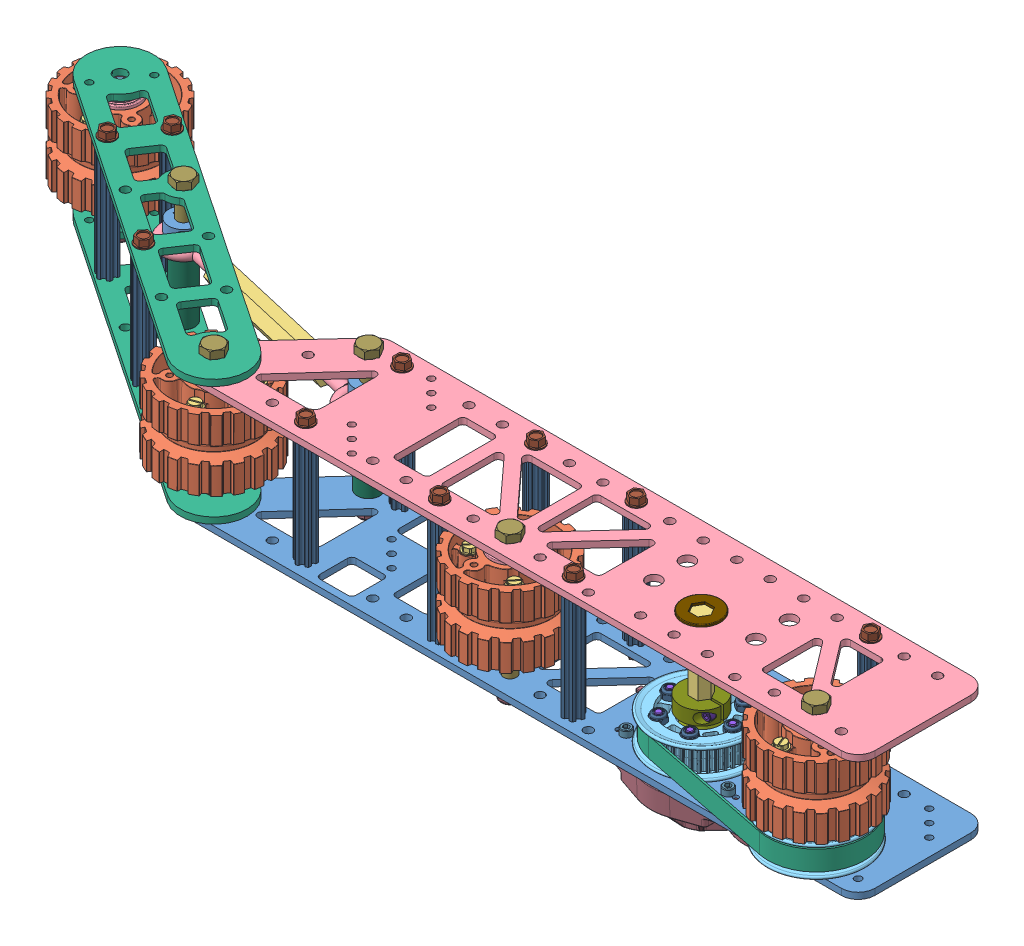
SolidWorks assembly TankDriveLeftSide, configuration Left Side. Lengths in mm.
Overall size (767.37 153.17 246.6).
161 component instances, 41 part files, 0 mates.
Components (placement in the parent):
- am-3319 Inside Plate-1: am-3319 Inside Plate [Default] at (-236.8957 -8.1516 48.6059) size (527.05 4.76 117.47)
- 20T pulley back to back-1: 20T pulley back to back [Default] at (-161.7045 40.7669 -11.83) x (0.939367 0 -0.342914) z (0.342914 0 0.939367) size (79.28 58.42 79.28)
  - am-3298 20 tooth Molded Tank Pulley Half r3-1: am-3298 20 tooth Molded Tank Pulley Half r3 [Default] at (-66.929 10.7589 19.6249) size (79.28 27.95 79.28)
  - am-3298 20 tooth Molded Tank Pulley Half r3-2: am-3298 20 tooth Molded Tank Pulley Half r3 [Default] at (-66.929 10.7589 19.6249) x (1 0 0) z (0 0 -1) size (79.28 27.95 79.28)
  - 10-24 Hex Washer Rolling x 1.25_93882A213-1: 10-24 Hex Washer Rolling x 1.25_93882A213 [Default] at (-46.3067 30.1899 7.7187) x (1 0 0) z (0 1 0) size (10.52 10.52 35.59)
  - 10-24 Hex Washer Rolling x 1.25_93882A213-2: 10-24 Hex Washer Rolling x 1.25_93882A213 [Default] at (-87.5512 30.1899 7.7187) x (1 0 0) z (0 1 0) size (10.52 10.52 35.59)
  - 10-24 Hex Washer Rolling x 1.25_93882A213-3: 10-24 Hex Washer Rolling x 1.25_93882A213 [Default] at (-66.929 30.1899 43.4374) x (1 0 0) z (0 1 0) size (10.52 10.52 35.59)
  - 10-24 Hex Washer Rolling x 1.25_93882A213-4: 10-24 Hex Washer Rolling x 1.25_93882A213 [Default] at (-66.929 -8.6721 -4.1876) x (-0.837169 0 -0.546944) z (0 -1 0) size (10.52 10.52 35.59)
  - 10-24 Hex Washer Rolling x 1.25_93882A213-5: 10-24 Hex Washer Rolling x 1.25_93882A213 [Default] at (-87.5512 -8.6721 31.5312) x (-0.837169 0 -0.546944) z (0 -1 0) size (10.52 10.52 35.59)
  - 10-24 Hex Washer Rolling x 1.25_93882A213-6: 10-24 Hex Washer Rolling x 1.25_93882A213 [Default] at (-46.3067 -8.6721 31.5312) x (-0.837169 0 -0.546944) z (0 -1 0) size (10.52 10.52 35.59)
  - 1614Z Bearing-1: 1614Z Bearing [Default] at (-66.929 -13.6886 19.6249) x (1 0 0) z (0 1 0) size (28.58 28.58 9.53)
  - 1614Z Bearing-2: 1614Z Bearing [Default] at (-66.929 35.2064 19.6249) x (1 0 0) z (0 -1 0) size (28.58 28.58 9.53)
- am-1393 375 washer-1: am-1393 375 washer [Default] at (-217.8457 80.7357 29.5559) size (20.62 1.6 20.62)
- am-3320 Upper Bar-1: am-3320 Upper Bar [Default] at (-436.3178 87.0984 -117.8054) x (0.829038 0 0.559193) z (-0.559193 0 0.829038) size (314.32 4.76 50.8)
- am-3320 Upper Bar-2: am-3320 Upper Bar [Default] at (-436.3178 -3.3891 -117.8054) x (0.829038 0 0.559193) z (-0.559193 0 0.829038) size (314.32 4.76 50.8)
- 20T pulley back to back-2: 20T pulley back to back [Default] at (-369.3889 40.7669 -137.4304) size (79.28 58.42 79.28)
  - am-3298 20 tooth Molded Tank Pulley Half r3-1: am-3298 20 tooth Molded Tank Pulley Half r3 [Default] at (-66.929 10.7589 19.6249) size (79.28 27.95 79.28)
  - am-3298 20 tooth Molded Tank Pulley Half r3-2: am-3298 20 tooth Molded Tank Pulley Half r3 [Default] at (-66.929 10.7589 19.6249) x (1 0 0) z (0 0 -1) size (79.28 27.95 79.28)
  - 10-24 Hex Washer Rolling x 1.25_93882A213-1: 10-24 Hex Washer Rolling x 1.25_93882A213 [Default] at (-46.3067 30.1899 7.7187) x (1 0 0) z (0 1 0) size (10.52 10.52 35.59)
  - 10-24 Hex Washer Rolling x 1.25_93882A213-2: 10-24 Hex Washer Rolling x 1.25_93882A213 [Default] at (-87.5512 30.1899 7.7187) x (1 0 0) z (0 1 0) size (10.52 10.52 35.59)
  - 10-24 Hex Washer Rolling x 1.25_93882A213-3: 10-24 Hex Washer Rolling x 1.25_93882A213 [Default] at (-66.929 30.1899 43.4374) x (1 0 0) z (0 1 0) size (10.52 10.52 35.59)
  - 10-24 Hex Washer Rolling x 1.25_93882A213-4: 10-24 Hex Washer Rolling x 1.25_93882A213 [Default] at (-66.929 -8.6721 -4.1876) x (-0.837169 0 -0.546944) z (0 -1 0) size (10.52 10.52 35.59)
  - 10-24 Hex Washer Rolling x 1.25_93882A213-5: 10-24 Hex Washer Rolling x 1.25_93882A213 [Default] at (-87.5512 -8.6721 31.5312) x (-0.837169 0 -0.546944) z (0 -1 0) size (10.52 10.52 35.59)
  - 10-24 Hex Washer Rolling x 1.25_93882A213-6: 10-24 Hex Washer Rolling x 1.25_93882A213 [Default] at (-46.3067 -8.6721 31.5312) x (-0.837169 0 -0.546944) z (0 -1 0) size (10.52 10.52 35.59)
  - 1614Z Bearing-1: 1614Z Bearing [Default] at (-66.929 -13.6886 19.6249) x (1 0 0) z (0 1 0) size (28.58 28.58 9.53)
  - 1614Z Bearing-2: 1614Z Bearing [Default] at (-66.929 35.2064 19.6249) x (1 0 0) z (0 -1 0) size (28.58 28.58 9.53)
- Track Belt-1: Track Belt [Default] at (269.5295 26.1257 93.0559) (suppressed, hidden)
- am-2598_107 2016 KOP Toughbox Mini-1: am-2598_107 2016 KOP Toughbox Mini [Default] at (224.1992 42.3901 20.5759) x (0.999999 0 -0.001296) z (0 1 0) size (140.05 121.81 142.29)
  - Toughbox d07-1: Toughbox d07 [Default] at (-88.5589 93.4503 -52.3959) x (-0.336928 0.94153 0) z (0.94153 0.336928 0) size (11 38.23 9.52)
  - Toughbox d05-1: Toughbox d05 [Default] at (-91.0349 50.9043 -67.5597) x (-0.336928 0.94153 0) z (0 0 -1) size (65.97 66.04 10.34)
  - FR6ZZ Bearing-1: FR6ZZ Bearing [Default] at (-96.247 60.278 -52.5991) x (-0.893862 0.448342 0) z (0 0 1) size (24.69 24.69 7.16)
  - 10-32 Nylock Nut-1: 10-32 Nylock Nut [Default] at (-129.8464 -8.0737 -56.3837) x (0.501678 0.865055 0) z (0 0 -1) size (9.53 11 5.96)
  - 10-32 Nylock Nut-2: 10-32 Nylock Nut [Default] at (-59.2462 80.7349 -56.3837) x (0.999999 -0.001296 0) z (0 0 -1) size (9.53 11 5.96)
  - 10-32 Nylock Nut-3: 10-32 Nylock Nut [Default] at (-122.7461 80.8172 -56.3837) x (0.500567 0.865698 0) z (0 0 -1) size (9.53 11 5.96)
  - 10-32 Nylock Nut-4: 10-32 Nylock Nut [Default] at (-52.3764 -8.1741 -56.3837) x (-0.501678 -0.865055 0) z (0 0 -1) size (9.53 11 5.96)
  - 5-16 washer-1: 5-16 washer [Default] at (-52.3162 38.3079 -77.7705) x (0.38418 -0.923258 0) z (0 0 -1) size (17.53 17.53 1.47)
  - 5-16 washer-2: 5-16 washer [Default] at (-52.3162 38.3079 -76.2973) x (0.897267 -0.441488 0) z (0 0 -1) size (17.53 17.53 1.47)
  - 5-16 washer-3: 5-16 washer [Default] at (-129.7861 38.4083 -77.7705) x (-0.990116 0.140253 0) z (0 0 1) size (17.53 17.53 1.47)
  - 5-16 washer-4: 5-16 washer [Default] at (-129.7861 38.4083 -79.2437) x (-0.681761 0.731575 0) z (0 0 1) size (17.53 17.53 1.47)
  - Toughbox d09-1: Toughbox d09 [Default] at (-52.3162 38.3079 -63.5973) x (0.910249 -0.414061 0) z (0 0 -1) size (20.03 20.32 12.7)
  - Toughbox d09-2: Toughbox d09 [Default] at (-129.7861 38.4083 -63.5973) x (0.075368 -0.997156 0) z (0 0 -1) size (20.03 20.32 12.7)
  - TM Housing-1: TM Housing [Default] at (-91.0876 10.1882 -86.3557) x (0.999999 -0.001296 0) z (0 0 1) size (139.9 118.55 41.62)
  - SHCS 10-32 x 0.625-1: SHCS 10-32 x 0.625 [Default] at (-52.2832 63.7078 -74.4685) x (-0.564778 -0.825243 0) z (-0.825243 0.564778 0) size (7.82 20.65 7.82)
  - SHCS 10-32 x 0.625-2: SHCS 10-32 x 0.625 [Default] at (-52.3491 12.9079 -74.4685) x (-0.564778 -0.825243 0) z (-0.825243 0.564778 0) size (7.82 20.65 7.82)
  - SHCS 10-32 x 0.625-3: SHCS 10-32 x 0.625 [Default] at (-129.7532 63.8083 -74.4685) x (-0.966277 -0.257503 0) z (-0.257503 0.966277 0) size (7.82 20.65 7.82)
  - SHCS 10-32 x 0.625-4: SHCS 10-32 x 0.625 [Default] at (-129.819 13.0083 -74.4685) x (-0.99652 0.083357 0) z (0.083357 0.99652 0) size (7.82 20.65 7.82)
  - R6ZZ Bearing-1: R6ZZ Bearing [Default] at (-91.0349 50.9043 -84.8317) x (0.958138 -0.286306 0) z (0 0 1) size (22.23 22.23 7.11)
  - R6ZZ Bearing-2: R6ZZ Bearing [Default] at (-91.0876 10.1882 -84.8317) x (-0.328282 -0.94458 0) z (0 0 1) size (22.23 22.23 7.11)
  - 8mm spring clip-1: 8mm spring clip [Default] at (-129.7861 38.4083 -63.5973) x (0 0 1) z (-1 0 0) size (1.12 14.83 14.83)
  - 8mm spring clip-2: 8mm spring clip [Default] at (-52.3162 38.3079 -63.5973) x (0 0 1) z (-1 0 0) size (1.12 14.83 14.83)
  - 500 E-klip-1: 500 E-klip [Default] at (-91.0876 10.1882 -64.4355) x (0.996411 -0.084651 0) z (0 0 1) size (19.07 20.96 1.27)
  - FR8ZZ Hex Bearing-1: FR8ZZ Hex Bearing [Default] at (-91.0876 10.1882 -44.6717) x (-0.5 0.866025 0) z (0 0 -1) size (31.12 31.12 7.93)
  - 16t 20dp 375h with teeth-1: 16t 20dp 375h with teeth [Default] at (-91.0349 50.9043 -67.5597) x (0 0 1) z (-0.983853 0.178977 0) size (15.19 22.57 22.57)
  - 48t 20dp 500h with teeth-1: 48t 20dp 500h with teeth [Default] at (-91.0876 10.1882 -63.1655) x (0 0 1) z (-1 0 0) size (10.21 63.42 63.42)
  - TB Output Shaft Hex L-Base 2-1: TB Output Shaft Hex L-Base 2 [Default] at (-52.7805 -6.4809 -52.3197) x (1 0 0) z (0 -1 0) size (14.66 142.29 12.7)
- am-3318 Outside Plate-1: am-3318 Outside Plate [Default] at (-236.8957 82.3359 48.6059) size (527.05 4.76 98.42)
- 20T pulley back to back-3: 20T pulley back to back [Default] at (195.7467 40.7669 -24.8773) x (-0.380384 0 -0.924829) z (0.924829 0 -0.380384) size (79.28 58.42 79.28)
  - am-3298 20 tooth Molded Tank Pulley Half r3-1: am-3298 20 tooth Molded Tank Pulley Half r3 [Default] at (-66.929 10.7589 19.6249) size (79.28 27.95 79.28)
  - am-3298 20 tooth Molded Tank Pulley Half r3-2: am-3298 20 tooth Molded Tank Pulley Half r3 [Default] at (-66.929 10.7589 19.6249) x (1 0 0) z (0 0 -1) size (79.28 27.95 79.28)
  - 10-24 Hex Washer Rolling x 1.25_93882A213-1: 10-24 Hex Washer Rolling x 1.25_93882A213 [Default] at (-46.3067 30.1899 7.7187) x (1 0 0) z (0 1 0) size (10.52 10.52 35.59)
  - 10-24 Hex Washer Rolling x 1.25_93882A213-2: 10-24 Hex Washer Rolling x 1.25_93882A213 [Default] at (-87.5512 30.1899 7.7187) x (1 0 0) z (0 1 0) size (10.52 10.52 35.59)
  - 10-24 Hex Washer Rolling x 1.25_93882A213-3: 10-24 Hex Washer Rolling x 1.25_93882A213 [Default] at (-66.929 30.1899 43.4374) x (1 0 0) z (0 1 0) size (10.52 10.52 35.59)
  - 10-24 Hex Washer Rolling x 1.25_93882A213-4: 10-24 Hex Washer Rolling x 1.25_93882A213 [Default] at (-66.929 -8.6721 -4.1876) x (-0.837169 0 -0.546944) z (0 -1 0) size (10.52 10.52 35.59)
  - 10-24 Hex Washer Rolling x 1.25_93882A213-5: 10-24 Hex Washer Rolling x 1.25_93882A213 [Default] at (-87.5512 -8.6721 31.5312) x (-0.837169 0 -0.546944) z (0 -1 0) size (10.52 10.52 35.59)
  - 10-24 Hex Washer Rolling x 1.25_93882A213-6: 10-24 Hex Washer Rolling x 1.25_93882A213 [Default] at (-46.3067 -8.6721 31.5312) x (-0.837169 0 -0.546944) z (0 -1 0) size (10.52 10.52 35.59)
  - 1614Z Bearing-1: 1614Z Bearing [Default] at (-66.929 -13.6886 19.6249) x (1 0 0) z (0 1 0) size (28.58 28.58 9.53)
  - 1614Z Bearing-2: 1614Z Bearing [Default] at (-66.929 35.2064 19.6249) x (1 0 0) z (0 -1 0) size (28.58 28.58 9.53)
- 20T pulley back to back-4: 20T pulley back to back [Default] at (38.0319 40.7669 -30.8257) x (0.634256 0 -0.773123) z (0.773123 0 0.634256) size (79.28 58.42 79.28)
  - am-3298 20 tooth Molded Tank Pulley Half r3-1: am-3298 20 tooth Molded Tank Pulley Half r3 [Default] at (-66.929 10.7589 19.6249) size (79.28 27.95 79.28)
  - am-3298 20 tooth Molded Tank Pulley Half r3-2: am-3298 20 tooth Molded Tank Pulley Half r3 [Default] at (-66.929 10.7589 19.6249) x (1 0 0) z (0 0 -1) size (79.28 27.95 79.28)
  - 10-24 Hex Washer Rolling x 1.25_93882A213-1: 10-24 Hex Washer Rolling x 1.25_93882A213 [Default] at (-46.3067 30.1899 7.7187) x (1 0 0) z (0 1 0) size (10.52 10.52 35.59)
  - 10-24 Hex Washer Rolling x 1.25_93882A213-2: 10-24 Hex Washer Rolling x 1.25_93882A213 [Default] at (-87.5512 30.1899 7.7187) x (1 0 0) z (0 1 0) size (10.52 10.52 35.59)
  - 10-24 Hex Washer Rolling x 1.25_93882A213-3: 10-24 Hex Washer Rolling x 1.25_93882A213 [Default] at (-66.929 30.1899 43.4374) x (1 0 0) z (0 1 0) size (10.52 10.52 35.59)
  - 10-24 Hex Washer Rolling x 1.25_93882A213-4: 10-24 Hex Washer Rolling x 1.25_93882A213 [Default] at (-66.929 -8.6721 -4.1876) x (-0.837169 0 -0.546944) z (0 -1 0) size (10.52 10.52 35.59)
  - 10-24 Hex Washer Rolling x 1.25_93882A213-5: 10-24 Hex Washer Rolling x 1.25_93882A213 [Default] at (-87.5512 -8.6721 31.5312) x (-0.837169 0 -0.546944) z (0 -1 0) size (10.52 10.52 35.59)
  - 10-24 Hex Washer Rolling x 1.25_93882A213-6: 10-24 Hex Washer Rolling x 1.25_93882A213 [Default] at (-46.3067 -8.6721 31.5312) x (-0.837169 0 -0.546944) z (0 -1 0) size (10.52 10.52 35.59)
  - 1614Z Bearing-1: 1614Z Bearing [Default] at (-66.929 -13.6886 19.6249) x (1 0 0) z (0 1 0) size (28.58 28.58 9.53)
  - 1614Z Bearing-2: 1614Z Bearing [Default] at (-66.929 35.2064 19.6249) x (1 0 0) z (0 -1 0) size (28.58 28.58 9.53)
- 42 - 2014 tooth pulley assembly-1: 42 - 2014 tooth pulley assembly [Default] at (239.3543 19.5217 29.5559) x (0 -1 0) z (0.610783 0 -0.791798) size (23.46 74.23 74.23)
  - 42 tooth HTD Pulley half 2014-1: 42 tooth HTD Pulley half 2014 [Default] at origin size (13 74.23 74.23)
  - 42 tooth HTD Pulley half 2014-2: 42 tooth HTD Pulley half 2014 [Default] at (16.6624 0 0) x (-1 0 0) z (0 0.000084 1) size (13 74.23 74.23)
- FR8ZZ Hex Bearing-1: FR8ZZ Hex Bearing [Default] at (133.0985 88.7393 10.5059) x (0.999999 0 -0.001296) z (0 -1 0) size (31.12 31.12 7.93)
- 425-5M-15-1: 425-5M-15 [Default] at (133.9257 4.5217 8.4615) x (0.980565 0 0.196193) z (-0.196193 0 0.980565) size (180.59 15 73.08)
- 500EX Hex Hub-1: 500EX Hex Hub [Default] at (133.0976 -2.2816 10.5059) x (0.999999 0 -0.001296) z (0.001296 0 0.999999) size (55.37 25.4 51.33)
- 42 - 2014 tooth pulley assembly-2: 42 - 2014 tooth pulley assembly [Default] at (133.0985 20.7308 10.5059) x (0 -1 0) z (-0.865387 0 0.501104) size (23.46 74.23 74.23)
  - 42 tooth HTD Pulley half 2014-1: 42 tooth HTD Pulley half 2014 [Default] at origin size (13 74.23 74.23)
  - 42 tooth HTD Pulley half 2014-2: 42 tooth HTD Pulley half 2014 [Default] at (16.6624 0 0) x (-1 0 0) z (0 0.000084 1) size (13 74.23 74.23)
- BHCS 10-32 x 1000_SBHCSCREW 0.19-32x0.5-HX-C-1: BHCS 10-32 x 1000_SBHCSCREW 0.19-32x0.5-HX-C [Default] at (121.2181 -1.799 31.1435) x (0 1 0) z (0 0 1) size (28.48 9.29 9.24)
- BHCS 10-32 x 1000_SBHCSCREW 0.19-32x0.5-HX-C-2: BHCS 10-32 x 1000_SBHCSCREW 0.19-32x0.5-HX-C [Default] at (109.2851 -1.799 10.5367) x (0 1 0) z (0 0 1) size (28.48 9.29 9.24)
- BHCS 10-32 x 1000_SBHCSCREW 0.19-32x0.5-HX-C-3: BHCS 10-32 x 1000_SBHCSCREW 0.19-32x0.5-HX-C [Default] at (121.1646 -1.799 -10.1009) x (0 1 0) z (0 0 1) size (28.48 9.29 9.24)
- BHCS 10-32 x 1000_SBHCSCREW 0.19-32x0.5-HX-C-4: BHCS 10-32 x 1000_SBHCSCREW 0.19-32x0.5-HX-C [Default] at (145.0306 -1.799 31.1126) x (0 1 0) z (0 0 1) size (28.48 9.29 9.24)
- BHCS 10-32 x 1000_SBHCSCREW 0.19-32x0.5-HX-C-5: BHCS 10-32 x 1000_SBHCSCREW 0.19-32x0.5-HX-C [Default] at (156.9101 -1.799 10.475) x (0 1 0) z (0 0 1) size (28.48 9.29 9.24)
- BHCS 10-32 x 1000_SBHCSCREW 0.19-32x0.5-HX-C-6: BHCS 10-32 x 1000_SBHCSCREW 0.19-32x0.5-HX-C [Default] at (144.9771 -1.799 -10.1318) x (0 1 0) z (0 0 1) size (28.48 9.29 9.24)
- 10-32 Nylock Nut-1: 10-32 Nylock Nut [Default] at (121.1642 19.7148 -10.1002) x (1 0 0) z (0 1 0) size (9.53 11 5.96)
- 10-32 Nylock Nut-2: 10-32 Nylock Nut [Default] at (144.9767 19.7148 -10.1315) x (1 0 0) z (0 1 0) size (9.53 11 5.96)
- 10-32 Nylock Nut-3: 10-32 Nylock Nut [Default] at (156.9101 19.7148 10.475) x (1 0 0) z (0 1 0) size (9.53 11 5.96)
- 10-32 Nylock Nut-4: 10-32 Nylock Nut [Default] at (121.2185 19.7148 31.1443) x (1 0 0) z (0 1 0) size (9.53 11 5.96)
- 10-32 Nylock Nut-5: 10-32 Nylock Nut [Default] at (109.2851 19.7148 10.5377) x (1 0 0) z (0 1 0) size (9.53 11 5.96)
- 10-32 Nylock Nut-6: 10-32 Nylock Nut [Default] at (145.031 19.7148 31.1129) x (1 0 0) z (0 1 0) size (9.53 11 5.96)
- 0985x0420 PVC Spacer-1: 0985x0420 PVC Spacer [Default] at (239.3543 -3.3891 29.5559) x (-0.937143 0 -0.348946) z (0.348946 0 -0.937143) size (17.27 25.4 17.27)
- Churro-1: Churro [3.375in] at (-141.6457 82.3359 -37.1191) x (-0.849392 0 -0.527763) z (0 -1 0) size (14.66 12.7 85.72)
- Churro-2: Churro [3.375in] at (213.9543 -3.3891 -37.1191) x (1 0 0) z (0 1 0) size (14.66 12.7 85.72)
- Churro-3: Churro [3.375in] at (-40.0457 -3.3891 35.9059) x (0.985635 0 -0.168888) z (0 1 0) size (14.66 12.7 85.72)
- Churro-4: Churro [3.375in] at (-141.6457 -3.3891 35.9059) x (0.827953 0 0.560798) z (0 1 0) size (14.66 12.7 85.72)
- Churro-5: Churro [3.375in] at (61.5543 -3.3891 35.9059) x (-0.985726 0 0.168355) z (0 1 0) size (14.66 12.7 85.72)
- Churro-6: Churro [3.375in] at (36.1543 -3.3891 -37.1191) x (-0.759985 0 0.649941) z (0 1 0) size (14.66 12.7 85.72)
- Churro-7: Churro [3.375in] at (-40.0457 82.3359 -37.1191) x (-0.946169 0 -0.323672) z (0 -1 0) size (14.66 12.7 85.72)
- FHTS 0.25-20-0.75_FHTS 0.25-20-G-0.75-C-1: FHTS 0.25-20-0.75_FHTS 0.25-20-G-0.75-C [Default] at (213.9543 -8.1516 -37.1191) x (0 1 0) z (0 0 1) size (24.64 12.19 12.19)
- FHTS 0.25-20-0.75_FHTS 0.25-20-G-0.75-C-2: FHTS 0.25-20-0.75_FHTS 0.25-20-G-0.75-C [Default] at (36.1543 -8.1516 -37.1191) x (0 1 0) z (0 0 1) size (24.64 12.19 12.19)
- FHTS 0.25-20-0.75_FHTS 0.25-20-G-0.75-C-3: FHTS 0.25-20-0.75_FHTS 0.25-20-G-0.75-C [Default] at (-141.6457 -8.1516 -37.1191) x (0 1 0) z (0 0 1) size (24.64 12.19 12.19)
- FHTS 0.25-20-0.75_FHTS 0.25-20-G-0.75-C-4: FHTS 0.25-20-0.75_FHTS 0.25-20-G-0.75-C [Default] at (-141.6457 -8.1516 35.9059) x (0 1 0) z (0 0 1) size (24.64 12.19 12.19)
- FHTS 0.25-20-0.75_FHTS 0.25-20-G-0.75-C-5: FHTS 0.25-20-0.75_FHTS 0.25-20-G-0.75-C [Default] at (-40.0457 -8.1516 35.9059) x (0 1 0) z (0 0 1) size (24.64 12.19 12.19)
- FHTS 0.25-20-0.75_FHTS 0.25-20-G-0.75-C-6: FHTS 0.25-20-0.75_FHTS 0.25-20-G-0.75-C [Default] at (61.5543 -8.1516 35.9059) x (0 1 0) z (0 0 1) size (24.64 12.19 12.19)
- FHTS 0.25-20-0.75_FHTS 0.25-20-G-0.75-C-7: FHTS 0.25-20-0.75_FHTS 0.25-20-G-0.75-C [Default] at (61.5543 87.0984 35.9059) x (0 -1 0) z (0 0 1) size (24.64 12.19 12.19)
- FHTS 0.25-20-0.75_FHTS 0.25-20-G-0.75-C-8: FHTS 0.25-20-0.75_FHTS 0.25-20-G-0.75-C [Default] at (36.1543 87.0984 -37.1191) x (0 -1 0) z (0 0 1) size (24.64 12.19 12.19)
- FHTS 0.25-20-0.75_FHTS 0.25-20-G-0.75-C-9: FHTS 0.25-20-0.75_FHTS 0.25-20-G-0.75-C [Default] at (213.9543 87.0984 -37.1191) x (0 -1 0) z (0.484299 0 -0.874902) size (24.64 12.19 12.19)
- FHTS 0.25-20-0.75_FHTS 0.25-20-G-0.75-C-10: FHTS 0.25-20-0.75_FHTS 0.25-20-G-0.75-C [Default] at (-40.0457 87.0984 -37.1191) x (0 -1 0) z (0 0 1) size (24.64 12.19 12.19)
- FHTS 0.25-20-0.75_FHTS 0.25-20-G-0.75-C-11: FHTS 0.25-20-0.75_FHTS 0.25-20-G-0.75-C [Default] at (-40.0457 87.0984 35.9059) x (0 -1 0) z (0 0 1) size (24.64 12.19 12.19)
- FHTS 0.25-20-0.75_FHTS 0.25-20-G-0.75-C-12: FHTS 0.25-20-0.75_FHTS 0.25-20-G-0.75-C [Default] at (-141.6457 87.0984 35.9059) x (0 -1 0) z (0 0 1) size (24.64 12.19 12.19)
- FHTS 0.25-20-0.75_FHTS 0.25-20-G-0.75-C-13: FHTS 0.25-20-0.75_FHTS 0.25-20-G-0.75-C [Default] at (-141.6457 87.0984 -37.1191) x (0 -1 0) z (0 0 1) size (24.64 12.19 12.19)
- FHTS 0.25-20-0.75_FHTS 0.25-20-G-0.75-C-14: FHTS 0.25-20-0.75_FHTS 0.25-20-G-0.75-C [Default] at (-40.0457 -8.1516 -37.1191) x (0 1 0) z (0 0 1) size (24.64 12.19 12.19)
- 375-16 x 4.25 Hex Bolt_HFBOLT 0.375-16x2.5x1-C-1: 375-16 x 4.25 Hex Bolt_HFBOLT 0.375-16x2.5x1-C [Default] at (239.3543 93.2706 29.5559) x (0 -1 0) z (0 0 1) size (114.12 16.48 14.28)
- 375-16 x 4.25 Hex Bolt_HFBOLT 0.375-16x2.5x1-C-2: 375-16 x 4.25 Hex Bolt_HFBOLT 0.375-16x2.5x1-C [Default] at (10.7543 93.2706 33.3659) x (0 -1 0) z (0 0 1) size (114.12 16.48 14.28)
- 3-8-16 NyLock Nut - Mcm 95615A140_95615A140-1: 3-8-16 NyLock Nut - Mcm 95615A140_95615A140 [Default] at (239.3543 -8.1516 29.5559) x (0.735076 0 0.677984) z (0.677984 0 -0.735076) size (14.29 12 16.5)
- 3-8-16 NyLock Nut - Mcm 95615A140_95615A140-2: 3-8-16 NyLock Nut - Mcm 95615A140_95615A140 [Default] at (10.7543 -8.1516 33.3659) x (0.995522 0 0.09453) z (0.09453 0 -0.995522) size (14.29 12 16.5)
- 3-8-16 NyLock Nut - Mcm 95615A140_95615A140-3: 3-8-16 NyLock Nut - Mcm 95615A140_95615A140 [Default] at (-436.3178 -3.3891 -117.8054) x (-0.761033 0 -0.648713) z (-0.648713 0 0.761033) size (14.29 12 16.5)
- 10-32x0625_shcs_HX-SHCS 0.19-32x1.375x1-C-1: 10-32x0625_shcs_HX-SHCS 0.19-32x1.375x1-C [Default] at (94.4397 1.4369 28.8193) x (0 -1 0) z (0 0 1) size (20.7 7.94 7.94)
- 10-32x0625_shcs_HX-SHCS 0.19-32x1.375x1-C-2: 10-32x0625_shcs_HX-SHCS 0.19-32x1.375x1-C [Default] at (171.7573 1.4369 28.8193) x (0 -1 0) z (0 0 1) size (20.7 7.94 7.94)
- 10-32x0625_shcs_HX-SHCS 0.19-32x1.375x1-C-3: 10-32x0625_shcs_HX-SHCS 0.19-32x1.375x1-C [Default] at (164.8485 1.4369 -60.0553) x (0 -1 0) z (0 0 1) size (20.7 7.94 7.94)
- 10-32x0625_shcs_HX-SHCS 0.19-32x1.375x1-C-4: 10-32x0625_shcs_HX-SHCS 0.19-32x1.375x1-C [Default] at (101.3485 1.4369 -60.0553) x (0 -1 0) z (0 0 1) size (20.7 7.94 7.94)
- FHTS 0.25-20-0.75_FHTS 0.25-20-G-0.75-C-15: FHTS 0.25-20-0.75_FHTS 0.25-20-G-0.75-C [Default] at (-400.1969 91.8609 -71.995) x (0 -1 0) z (0.620342 0 0.784332) size (24.64 12.19 12.19)
- FHTS 0.25-20-0.75_FHTS 0.25-20-G-0.75-C-16: FHTS 0.25-20-0.75_FHTS 0.25-20-G-0.75-C [Default] at (-315.9667 91.8609 -15.181) x (0 -1 0) z (0.315368 0 0.94897) size (24.64 12.19 12.19)
- am-1393 375 washer-2: am-1393 375 washer [Default] at (-436.3178 80.7357 -117.8054) size (20.62 1.6 20.62)
- 375-16 x 4.25 Hex Bolt_HFBOLT 0.375-16x2.5x1-C-3: 375-16 x 4.25 Hex Bolt_HFBOLT 0.375-16x2.5x1-C [Default] at (-163.8707 93.2706 -33.9441) x (0 -1 0) z (0.866025 0 0.5) size (114.12 16.48 14.28)
- 3-8-16 NyLock Nut - Mcm 95615A140_95615A140-4: 3-8-16 NyLock Nut - Mcm 95615A140_95615A140 [Default] at (-163.8707 -8.1516 -33.9441) x (-0.866025 0 -0.5) z (-0.5 0 0.866025) size (14.29 12 16.5)
- 3-8-16 NyLock Nut - Mcm 95615A140_95615A140-5: 3-8-16 NyLock Nut - Mcm 95615A140_95615A140 [Default] at (-340.3274 -3.3891 -69.9099) x (0.559193 0 -0.829038) z (-0.829038 0 -0.559193) size (14.29 12 16.5)
- 375-16 x 4.25 Hex Bolt_HFBOLT 0.375-16x2.5x1-C-4: 375-16 x 4.25 Hex Bolt_HFBOLT 0.375-16x2.5x1-C [Default] at (-340.3274 98.0331 -69.9099) x (0 -1 0) z (0.95519 0 -0.295994) size (114.12 16.48 14.28)
- am-0243 spacer 1860x0420-1: am-0243 spacer 1860x0420 [Default] at (-163.8707 -3.3891 -33.9441) x (1 0 0) z (0 1 0) size (17.27 17.27 47.24)
- am-0243 spacer 1860x0420-2: am-0243 spacer 1860x0420 [Default] at (-340.3274 1.3734 -69.9099) x (1 0 0) z (0 1 0) size (17.27 17.27 47.24)
- 500 Hex Collar Clamp-1: 500 Hex Collar Clamp [Default] at (198.3486 -8.4902 0.9895) x (0.999999 0 -0.001296) z (0.001296 0 0.999999) size (32.26 10.41 31.75)
  - Hex Collar 500-1: Hex Collar 500 [Default] at (-65.2624 31.6086 9.4318) size (31.73 10.41 31.75)
  - 8-32 x 0375 SHCS-1: 8-32 x 0375 SHCS [Default] at (-53.7269 36.8156 13.4323) x (0 0 -1) z (0.687397 0.726282 0) size (13.71 6.86 6.86)
- Churro-8: Churro [3.375in] at (-400.1969 87.0984 -71.995) x (0.898794 0 -0.438371) z (0 -1 0) size (14.66 12.7 85.72)
- Churro-9: Churro [3.375in] at (-315.9667 1.3734 -15.181) x (0.829038 0 0.559193) z (0 1 0) size (14.66 12.7 85.72)
- 375-16 x 4.25 Hex Bolt_HFBOLT 0.375-16x2.5x1-C-5: 375-16 x 4.25 Hex Bolt_HFBOLT 0.375-16x2.5x1-C [Default] at (-217.8457 98.0331 29.5559) x (0 -1 0) z (0 0 1) size (114.12 16.48 14.28)
- 3-8-16 NyLock Nut - Mcm 95615A140_95615A140-6: 3-8-16 NyLock Nut - Mcm 95615A140_95615A140 [Default] at (-217.8457 -8.1516 29.5559) x (-0.837169 0 -0.546944) z (-0.546944 0 0.837169) size (14.29 12 16.5)
- Spacer am-1181-1: Spacer am-1181 [Default] at (-163.8707 48.6301 -33.9441) x (1 0 0) z (0 1 0) size (19.05 19.05 4.78)
- Round Collar 375-1: Round Collar 375 [Default] at (-340.3274 59.6791 -69.9099) size (22.2 9.53 22.23)
- am-2243 brass spacer-1: am-2243 brass spacer [Default] at (-436.3178 9.293 -117.8054) x (1 0 0) z (0 1 0) size (11.1 11.1 20.83)
- am-2243 brass spacer-2: am-2243 brass spacer [Default] at (-217.8457 9.4073 29.5559) x (1 0 0) z (0 1 0) size (11.1 11.1 20.83)
- am-1393 375 washer-3: am-1393 375 washer [Default] at (-163.8707 48.6301 -33.9441) size (20.62 1.6 20.62)
- am-1393 375 washer-4: am-1393 375 washer [Default] at (-340.3274 50.2176 -69.9099) x (-0.837169 0 -0.546944) z (-0.546944 0 0.837169) size (20.62 1.6 20.62)
- am-3321 turnbuckle-1: am-3321 turnbuckle [Default] at (-104.1595 -20.3587 136.3613) x (0.97437 0 0.224951) z (0.224951 0 -0.97437) size (215.9 15.75 34.92)
  - Turnbuckle Body-1: Turnbuckle Body [Default] at (-241.5909 -75.2753 147.8583) size (111.12 15.75 18.18)
  - Turnbuckle Rod-1: Turnbuckle Rod [Default] at (-200.3159 -75.2753 147.8583) x (-1 0 0) z (0 0 -1) size (93.66 9.78 34.92)
  - Turnbuckle Rod-2: Turnbuckle Rod [Default] at (-171.7409 -75.2753 147.8583) size (93.66 9.78 34.92)
- Churro-10: Churro [3.375in] at (-380.312 1.3734 -101.4756) x (0.829038 0 0.559193) z (0 1 0) size (14.66 12.7 85.72)
- FHTS 0.25-20-0.75_FHTS 0.25-20-G-0.75-C-17: FHTS 0.25-20-0.75_FHTS 0.25-20-G-0.75-C [Default] at (-380.312 91.8609 -101.4756) x (0 -1 0) z (0.620342 0 0.784332) size (24.64 12.19 12.19)
- FHTS 0.25-20-0.75_FHTS 0.25-20-G-0.75-C-18: FHTS 0.25-20-0.75_FHTS 0.25-20-G-0.75-C [Default] at (-380.312 -3.3891 -101.4756) x (0 1 0) z (-0.948316 0 0.317326) size (24.64 12.19 12.19)
- Round Collar 375-2: Round Collar 375 [Default] at (-163.8707 59.6791 -33.9441) size (22.2 9.53 22.23)
- FHTS 0.25-20-0.75_FHTS 0.25-20-G-0.75-C-19: FHTS 0.25-20-0.75_FHTS 0.25-20-G-0.75-C [Default] at (-315.9667 -3.3891 -15.181) x (0 1 0) z (-0.948316 0 0.317326) size (24.64 12.19 12.19)
